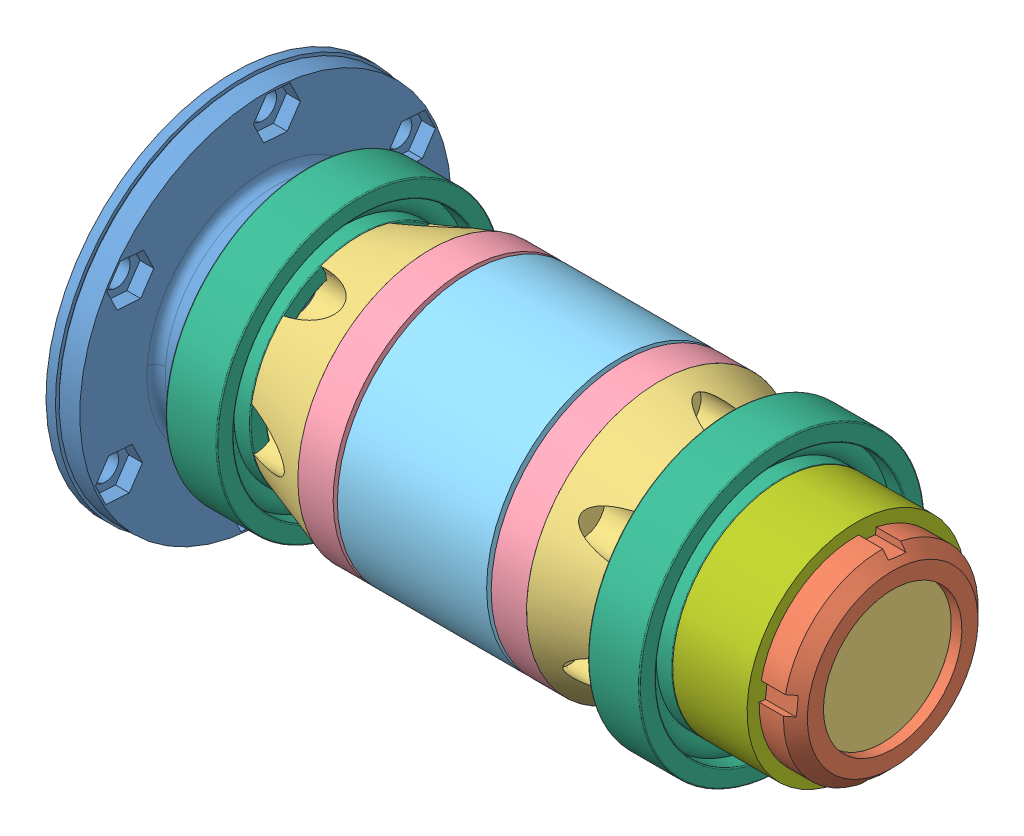
SolidWorks assembly quaife, configuration Default. Lengths in mm.
Overall size (238.24 140.51 140.51).
11 component instances, 7 part files, 0 mates.
Components (placement in the parent):
- DAA107x-1: DAA107x [Default] at (110.5343 226.8851 124.6281) x (1 0 0) z (0 0.069526 0.99758) size (40.89 131.67 131.67)
- DAA104-1: DAA104 [Default] at (-111.7408 245.6703 -81.5787) x (-1 0 0) z (0 0.248643 -0.968595) size (10 67.91 67.91)
- DAA104-2: DAA104 [Default] at (111.7408 232.0553 114.7141) x (1 0 0) z (0 0.11254 0.993647) size (10 67.91 67.91)
- daa101-1: daa101 [Default] at (110.5343 257.6984 24.5051) x (1 0 0) z (0 0.459188 0.888339) size (78.03 93.22 93.22)
- DAA102-1: DAA102 [Default] at (-110.5343 -50.3551 -253.916) x (-1 0 0) z (0 -0.930099 -0.367309) size (12.38 93.22 93.22)
- DAA106-1: DAA106 [Default] at (110.4218 -132.5606 222.3436) x (1 0 0) z (0 -0.999413 0.034263) size (62.48 93.22 93.22)
- daa101-2: daa101 [Default] at (-110.5343 -46.3671 -254.6745) x (-1 0 0) z (0 -0.924225 -0.381849) size (78.03 93.22 93.22)
- DAA102-2: DAA102 [Default] at (110.5343 -126.8259 -225.6638) x (1 0 0) z (0 0.467879 -0.883793) size (12.38 93.22 93.22)
- DAA103-1: DAA103 [Default] at (74.1299 -3.2907 140.0622) x (1 0 0) z (0 -0.023488 0.999724) size (18 100 100)
- DAA103-2: DAA103 [Default] at (-73.9089 21.8066 138.3933) x (1 0 0) z (0 0.155649 0.987812) size (18 100 100)
- DAA107y-1: DAA107y [Default] at (-110.5343 -64.4395 -250.712) x (-1 0 0) z (0 -0.949139 -0.314858) size (40.89 76.67 76.67)
